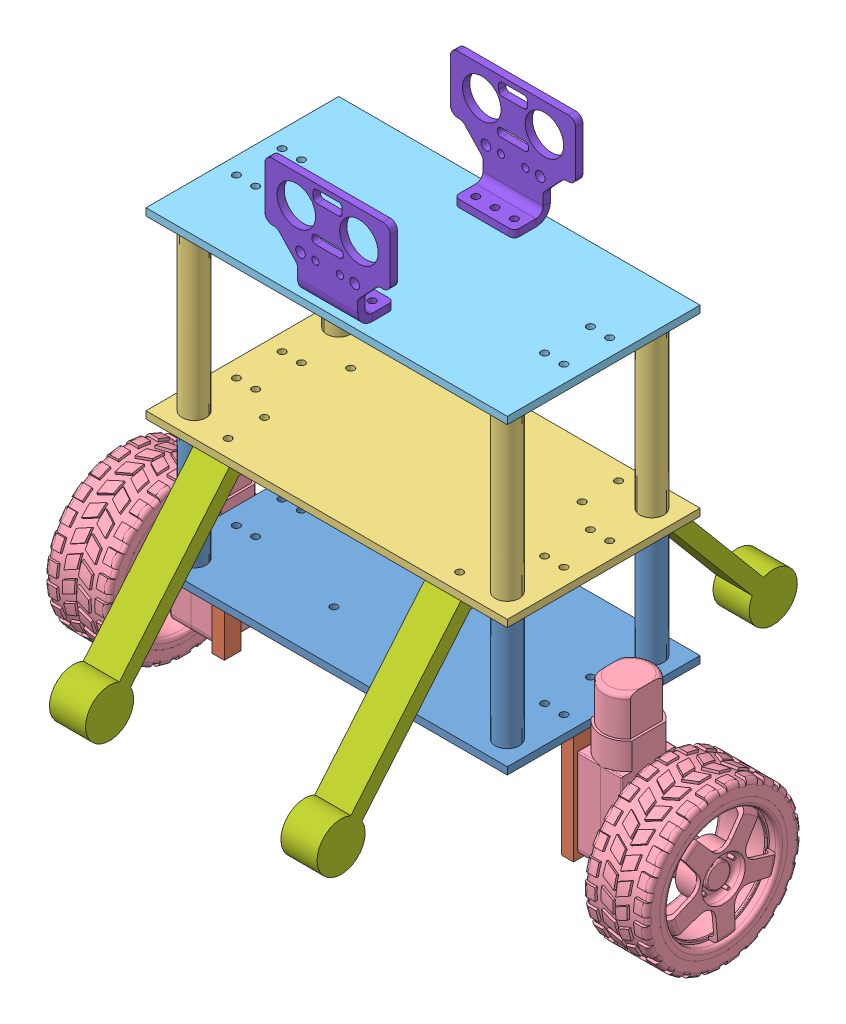
SolidWorks assembly Assem, configuration Default. Lengths in mm.
Overall size (249.82 245.17 199.41).
15 component instances, 9 part files, 38 mates.
Components (placement in the parent):
- base-1: base [Default] at (69.1272 71.7618 119.9447) size (150 53 80)
- motor mount-1: motor mount [Default] at (143.5935 63.7618 105.619) x (0 -1 0) z (0 0 -1) size (45 20 25)
- motor mount-2: motor mount [Default] at (-22.2685 63.7618 130.619) x (0 -1 0) z (0 0 1) size (45 20 25)
- 2ndbase-1: 2ndbase [Default] at (69.1272 121.7618 116.2933) x (1 0 0) z (0 0 -1) size (150 73 80)
- dc_motor_with_wheel-1: dc_motor_with_wheel [Défaut] at (163.4845 -16.1642 126.839) x (1 0 0) z (0 0.96637 -0.257157) size (59.31 65 86.68)
- dc_motor_with_wheel-2: dc_motor_with_wheel [Défaut] at (-42.1595 -16.1642 109.399) x (-1 0 0) z (0 0.96637 0.257157) size (59.31 65 86.68)
- 3rdbase-1: 3rdbase [Default] at (52.1978 194.7618 119.9447) x (-1 0 0) z (0 0 1) size (150 53 80)
- L298N Motor Driver.step-1: L298N Motor Driver.step [Default] at (61.0166 68.7618 117.9737) x (0.005567 0 -0.999985) z (-0.999985 0 -0.005567) size (43.5 26 43.5)
- angle-1: angle [Default] at (20.2602 116.7618 85.22) size (15 73.52 89.71)
- angle-2: angle [Default] at (116.3652 116.7618 85.22) size (15 73.52 89.71)
- angle-3: angle [Default] at (101.3652 116.7618 151.0179) x (-1 0 0) z (0 0 -1) size (15 73.52 89.71)
- angle-4: angle [Default] at (5.2602 116.7618 151.0179) x (-1 0 0) z (0 0 -1) size (15 73.52 89.71)
- soporte-1: soporte [temporal] at (61.0651 199.7618 81.119) x (-1 0 0) z (0 -1 0) size (52 15 44)
- soporte-2: soporte [temporal] at (61.0651 199.7618 155.119) x (1 0 0) z (0 -1 0) size (52 15 44)
- pillers-1: pillers [Default] at (-4.3375 69.7618 88.119) size (4.5 55 4.5)
Mates (geometry in assembly coordinates):
- Coincident1: coincident anti-aligned: plane of base-1 through (69.1272 68.7618 119.9447) normal (0 -1 0); plane of motor mount-1 through (135.6625 68.7618 130.619) normal (0 1 0)
- Coincident2: coincident aligned: plane of base-1 through (135.6625 68.7618 119.9447) normal (1 0 0); plane of motor mount-1 through (135.6625 23.7618 130.619) normal (1 0 0)
- Concentric1: concentric aligned: cylinder of base-1 through (120.6625 68.7618 127.619) axis (0 1 0) radius 1.5; axis of motor mount-1 through (120.6625 63.7618 127.619) axis (0 1 0)
- Coincident3: coincident anti-aligned: plane of base-1 through (69.1272 68.7618 119.9447) normal (0 -1 0); plane of motor mount-2 through (-14.3375 68.7618 105.619) normal (0 1 0)
- Coincident4: coincident aligned: plane of base-1 through (-14.3375 68.7618 119.9447) normal (-1 0 0); plane of motor mount-2 through (-14.3375 23.7618 105.619) normal (-1 0 0)
- Concentric2: concentric aligned: cylinder of base-1 through (0.6625 68.7618 127.619) axis (0 1 0) radius 1.5; cylinder of motor mount-2 through (0.6625 42.7618 127.619) axis (0 1 0) radius 1.5
- Coincident5: coincident anti-aligned: plane of base-1 through (125.6625 121.7618 88.119) normal (0 1 0); plane of 2ndbase-1 through (69.1272 121.7618 116.2933) normal (0 -1 0)
- Concentric3: concentric: cylinder of base-1 through (125.6625 121.7618 88.119) axis (0 -1 0) radius 2.5; cylinder of 2ndbase-1 through (125.6625 71.7618 88.119) axis (0 1 0) radius 2.25
- Concentric4: concentric: circle of base-1; cylinder of 2ndbase-1 through (-4.3375 71.7618 88.119) axis (0 1 0) radius 2.25
- Coincident6: coincident anti-aligned: plane of motor mount-2 through (-14.3375 23.7618 105.619) normal (-1 0 0); plane of dc_motor_with_wheel-2 through (-14.3375 36.3598 118.119) normal (1 0 0)
- Coincident7: coincident anti-aligned: plane of motor mount-1 through (135.6625 23.7618 130.619) normal (1 0 0); plane of dc_motor_with_wheel-1 through (135.6625 36.3598 118.119) normal (-1 0 0)
- Concentric5: concentric anti-aligned: circle of motor mount-2; cylinder of dc_motor_with_wheel-2 through (-33.1375 56.9598 126.869) axis (1 0 0) radius 1.5
- Concentric6: concentric anti-aligned: cylinder of motor mount-2 through (-4.3375 56.9598 109.369) axis (-1 0 0) radius 1.5; line of dc_motor_with_wheel-2 through (-33.1375 56.9598 109.369) axis (1 0 0)
- Concentric7: concentric anti-aligned: cylinder of motor mount-1 through (125.6625 56.9598 109.369) axis (1 0 0) radius 1.5; cylinder of dc_motor_with_wheel-1 through (154.4625 56.9598 109.369) axis (-1 0 0) radius 1.5
- Concentric8: concentric anti-aligned: cylinder of motor mount-1 through (125.6625 56.9598 126.869) axis (1 0 0) radius 1.5; cylinder of dc_motor_with_wheel-1 through (154.4625 56.9598 126.869) axis (-1 0 0) radius 1.5
- Coincident9: coincident anti-aligned: plane of 2ndbase-1 through (125.6625 194.7618 148.119) normal (0 1 0); plane of 3rdbase-1 through (52.1978 194.7618 119.9447) normal (0 -1 0)
- Concentric11: concentric anti-aligned: cylinder of 2ndbase-1 through (125.6625 194.7618 148.119) axis (0 -1 0) radius 2.5; cylinder of 3rdbase-1 through (125.6625 144.7618 148.119) axis (0 1 0) radius 2.25
- Concentric12: concentric anti-aligned: line of 2ndbase-1 through (-4.3375 194.7618 148.119) axis (0 -1 0); cylinder of 3rdbase-1 through (-4.3375 144.7618 148.119) axis (0 1 0) radius 2.25
- Coincident10: coincident anti-aligned: plane of base-1 through (69.1272 68.7618 119.9447) normal (0 -1 0); plane of L298N Motor Driver.step-1 through (61.0166 68.7618 117.9737) normal (0 1 0)
- Concentric13: concentric aligned: circle of base-1; circle of L298N Motor Driver.step-1
- Coincident11: coincident anti-aligned: plane of 2ndbase-1 through (69.1272 121.7618 116.2933) normal (0 -1 0); plane of angle-1 through (5.2602 121.7618 108.119) normal (0 1 0)
- Coincident12: coincident aligned: line of 2ndbase-1 through (-14.3375 121.7618 78.119) axis (1 0 0); line of angle-1 through (5.2602 121.7618 78.119) axis (1 0 0)
- Coincident13: coincident anti-aligned: plane of 2ndbase-1 through (69.1272 121.7618 116.2933) normal (0 -1 0); plane of angle-2 through (101.3652 121.7618 108.119) normal (0 1 0)
- Coincident14: coincident aligned: line of 2ndbase-1 through (-14.3375 121.7618 78.119) axis (1 0 0); line of angle-2 through (101.3652 121.7618 78.119) axis (1 0 0)
- Coincident15: coincident anti-aligned: plane of 2ndbase-1 through (69.1272 121.7618 116.2933) normal (0 -1 0); plane of angle-3 through (116.3652 121.7618 128.119) normal (0 1 0)
- Coincident16: coincident anti-aligned: line of 2ndbase-1 through (-14.3375 121.7618 158.119) axis (1 0 0); line of angle-3 through (116.3652 121.7618 158.119) axis (-1 0 0)
- Coincident17: coincident anti-aligned: plane of 2ndbase-1 through (69.1272 121.7618 116.2933) normal (0 -1 0); plane of angle-4 through (20.2602 121.7618 128.119) normal (0 1 0)
- Coincident18: coincident anti-aligned: line of 2ndbase-1 through (-14.3375 121.7618 158.119) axis (1 0 0); line of angle-4 through (20.2602 121.7618 158.119) axis (-1 0 0)
- Coincident19: coincident aligned: plane of angle-2 through (116.3652 58.2371 28.4139) normal (1 0 0); plane of angle-3 through (116.3652 58.2371 207.8241) normal (1 0 0)
- Coincident20: coincident aligned: plane of angle-1 through (5.2602 58.2371 28.4139) normal (-1 0 0); plane of angle-4 through (5.2602 58.2371 207.8241) normal (-1 0 0)
- Coincident21: coincident anti-aligned: plane of 3rdbase-1 through (52.1978 197.7618 119.9447) normal (0 1 0); plane of soporte-2 through (61.0651 197.7618 155.119) normal (0 -1 0)
- Coincident22: coincident aligned: plane of 3rdbase-1 through (52.1978 197.7618 158.119) normal (0 0 1); plane of soporte-2 through (61.0651 199.7618 158.119) normal (0 0 1)
- Coincident23: coincident anti-aligned: plane of 3rdbase-1 through (52.1978 197.7618 119.9447) normal (0 1 0); plane of soporte-1 through (61.0651 197.7618 81.119) normal (0 -1 0)
- Coincident24: coincident aligned: plane of 3rdbase-1 through (52.1978 197.7618 78.119) normal (0 0 -1); plane of soporte-1 through (61.0651 199.7618 78.119) normal (0 0 -1)
- Coincident25: coincident aligned: plane of soporte-1 through (87.0651 217.7618 78.119) normal (1 0 0); plane of soporte-2 through (87.0651 217.7618 158.119) normal (1 0 0)
- Coincident26: coincident anti-aligned: circle of 2ndbase-1; plane of pillers-1 through (-4.3375 124.7618 88.119) normal (0 1 0)
- Concentric14: concentric aligned: circle of 2ndbase-1; cylinder of pillers-1 through (-4.3375 124.7618 88.119) axis (0 -1 0) radius 2.25
- Concentric15: concentric anti-aligned: circle of base-1; cylinder of pillers-1 through (-4.3375 124.7618 88.119) axis (0 -1 0) radius 2.25
